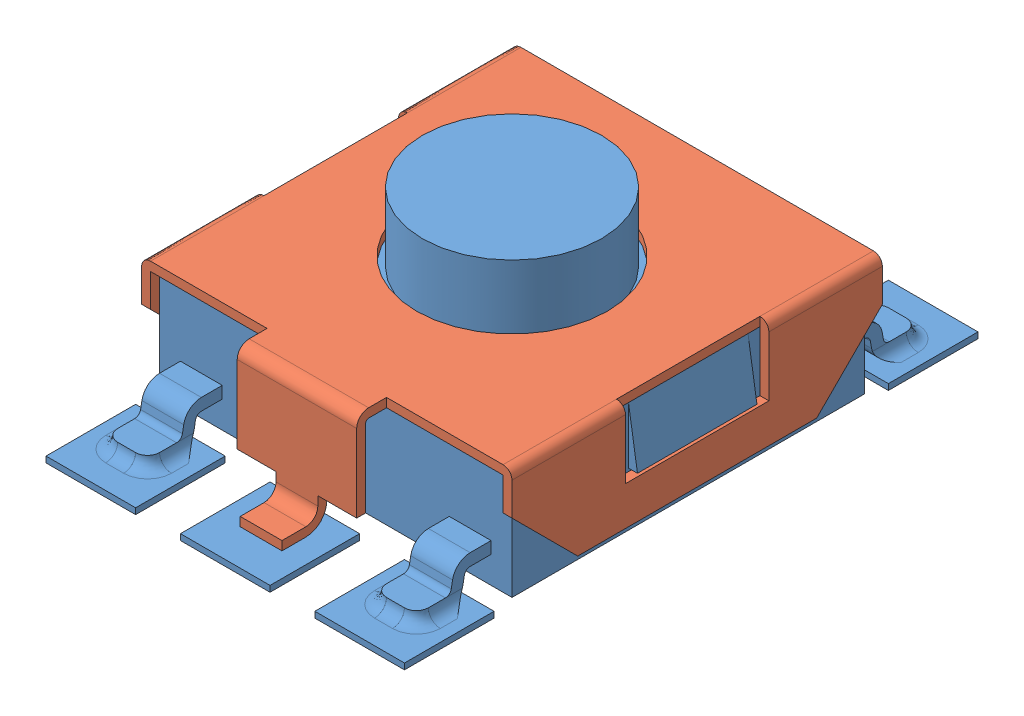
SolidWorks assembly RESET BUTTON, configuration Default. Lengths in mm.
Overall size (6.2 3.1 9.6).
2 component instances, 2 part files, 6 mates.
Components (placement in the parent):
- RESET CORE-1: RESET CORE [Default] at (0 0.1 0) x (-1 0 0) z (0 0 -1) size (6.2 3.1 9.6)
- RESET-1: RESET [Default] at (0 0.1 0) x (0 0 1) z (-1 0 0) size (7.3 2 6.2)
Mates (geometry in assembly coordinates):
- Coincident4: coincident: plane of RESET CORE-1 through (0 0.1 0) normal (0 0 -1); plane of assembly through (0 0 0) normal (0 0 1)
- Coincident5: coincident: plane of RESET CORE-1 through (0 0.1 0) normal (-1 0 0); plane of assembly through (0 0 0) normal (1 0 0)
- Coincident6: coincident: plane of RESET CORE-1 through (0 0 0) normal (0 -1 0); plane of assembly through (0 0 0) normal (0 1 0)
- Coincident7: coincident: plane of RESET-1 through (0 0.1 0) normal (0 0 1); plane of assembly through (0 0 0) normal (0 0 1)
- Coincident9: coincident: plane of RESET-1 through (0 0.1 0) normal (-1 0 0); plane of assembly through (0 0 0) normal (1 0 0)
- Coincident10: coincident: plane of RESET CORE-1; plane of RESET-1
